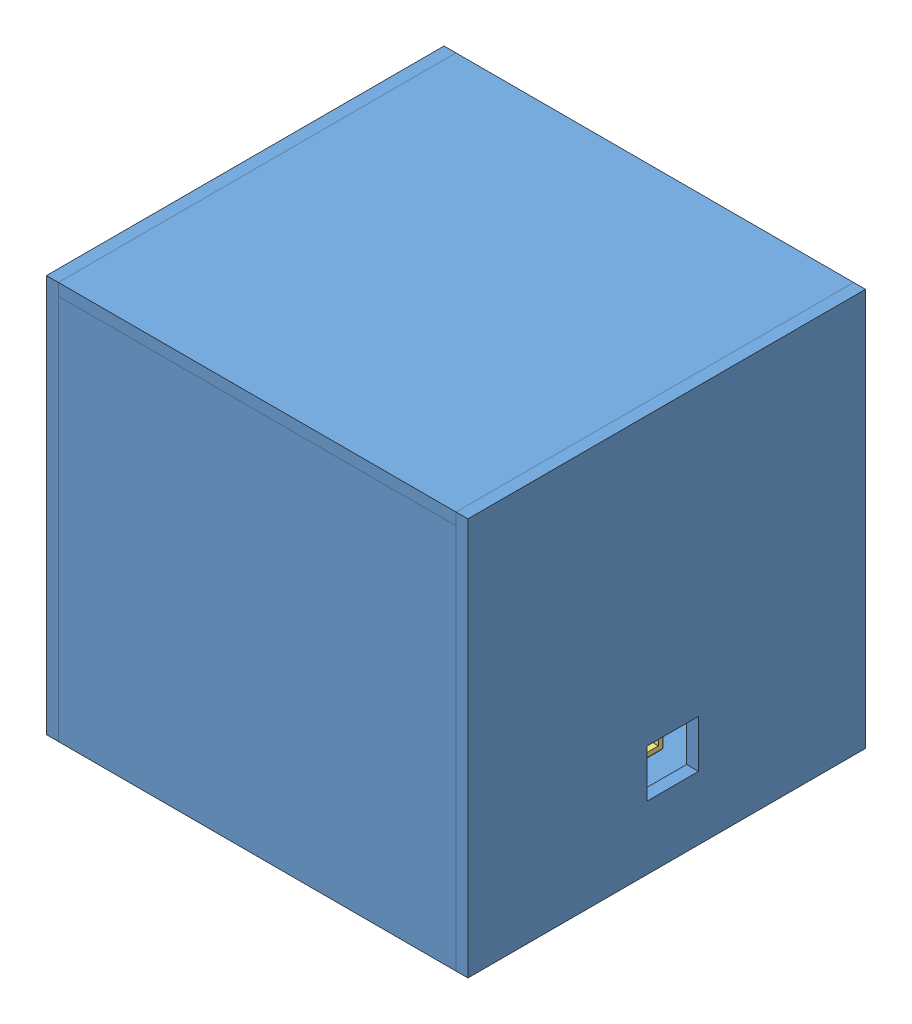
SolidWorks assembly config cube, configuration Default. Lengths in mm.
Overall size (106 103.17 100).
19 component instances, 4 part files, 36 mates.
Components (placement in the parent):
- Side-1: Side [holes] at (39.6067 40.9031 84.24) x (1 0 0) z (0 0 -1) size (100 3 94)
- 25x.5 Aluminum Hex Female Female Standoff-1: 25x.5 Aluminum Hex Female Female Standoff [Default] at (63.0067 47.2531 95.54) x (-0.497052 0 0.867721) z (0 1 0) size (6.35 8.06 12.7)
- 25x.5 Aluminum Hex Female Female Standoff-2: 25x.5 Aluminum Hex Female Female Standoff [Default] at (12.2067 47.2531 80.24) x (-0.915695 0 -0.401873) z (0 1 0) size (6.35 8.06 12.7)
- 25x.5 Aluminum Hex Female Female Standoff-3: 25x.5 Aluminum Hex Female Female Standoff [Default] at (12.2067 47.2531 52.34) x (0.973443 0 -0.22893) z (0 1 0) size (6.35 8.06 12.7)
- 25x.5 Aluminum Hex Female Female Standoff-4: 25x.5 Aluminum Hex Female Female Standoff [Default] at (64.6067 47.2531 47.24) x (-0.96108 0 -0.27627) z (0 1 0) size (6.35 8.06 12.7)
- ArduinoUno-1: ArduinoUno [Default] at (45.6067 53.6031 71.39) x (-1 0 0) z (0 0 -1) size (74.8 12.1 53.3)
- socket head cap screw_ai-2: socket head cap screw_ai [HX-SHCS 0.125-40x0.125x0.125-N] at (63.0067 58.3781 95.54) x (0 -1 0) z (0 0 1) size (6.35 5.21 5.21)
- socket head cap screw_ai-3: socket head cap screw_ai [HX-SHCS 0.125-40x0.125x0.125-N] at (12.2067 58.3781 80.24) x (0 -1 0) z (0 0 1) size (6.35 5.21 5.21)
- socket head cap screw_ai-4: socket head cap screw_ai [HX-SHCS 0.125-40x0.125x0.125-N] at (64.6067 58.3781 47.24) x (0 -1 0) z (0 0 1) size (6.35 5.21 5.21)
- socket head cap screw_ai-5: socket head cap screw_ai [HX-SHCS 0.125-40x0.125x0.125-N] at (12.2067 58.3781 52.34) x (0 -1 0) z (0 0 1) size (6.35 5.21 5.21)
- socket head cap screw_ai-6: socket head cap screw_ai [HX-SHCS 0.125-40x0.125x0.125-N] at (12.2067 34.7281 52.34) x (0 1 0) z (0 0 1) size (6.35 5.21 5.21)
- socket head cap screw_ai-7: socket head cap screw_ai [HX-SHCS 0.125-40x0.125x0.125-N] at (12.2067 34.7281 80.24) x (0 1 0) z (0 0 1) size (6.35 5.21 5.21)
- Side-3: Side [left right] at (-10.3933 87.9031 84.24) x (0 -1 0) z (0 0 -1) size (100 3 100)
- Side-4: Side [front back] at (39.6067 86.4031 131.24) x (1 0 0) z (0 -1 0) size (100 3 97)
- Side-5: Side [front back] at (39.6067 86.4031 34.24) x (1 0 0) z (0 -1 0) size (100 3 97)
- Side-6: Side [no holes] at (39.6067 137.9031 84.24) x (1 0 0) z (0 0 -1) size (100 3 100)
- Side-8: Side [left right hole] at (89.6067 87.9031 84.24) x (0 0 -1) z (0 -1 0) size (100 3 100)
- socket head cap screw_ai-13: socket head cap screw_ai [HX-SHCS 0.125-40x0.125x0.125-N] at (63.0067 34.7281 95.54) x (0 1 0) z (0 0 1) size (6.35 5.21 5.21)
- socket head cap screw_ai-14: socket head cap screw_ai [HX-SHCS 0.125-40x0.125x0.125-N] at (64.6067 34.7281 47.24) x (0 1 0) z (0 0 1) size (6.35 5.21 5.21)
Mates (geometry in assembly coordinates):
- Concentric5: concentric aligned: circle of 25x.5 Aluminum Hex Female Female Standoff-2; circle of ArduinoUno-1
- Coincident9: coincident anti-aligned: plane of 25x.5 Aluminum Hex Female Female Standoff-2 through (12.2067 53.6031 80.24) normal (0 1 0); plane of ArduinoUno-1 through (12.6067 53.6031 98.04) normal (0 -1 0)
- Concentric6: concentric anti-aligned: cylinder of ArduinoUno-1 through (63.0067 55.2031 95.54) axis (0 -1 0) radius 1.6; cylinder of socket head cap screw_ai-2 through (63.0067 90.1281 95.54) axis (0 1 0) radius 2.6035
- Coincident11: coincident anti-aligned: plane of ArduinoUno-1 through (12.6067 55.2031 98.04) normal (0 1 0); plane of socket head cap screw_ai-2 through (65.6102 55.2031 95.54) normal (0 -1 0)
- Concentric7: concentric anti-aligned: cylinder of ArduinoUno-1 through (12.2067 55.2031 80.24) axis (0 -1 0) radius 1.6; cylinder of socket head cap screw_ai-3 through (12.2067 90.1281 80.24) axis (0 1 0) radius 2.6035
- Coincident12: coincident anti-aligned: plane of ArduinoUno-1 through (12.6067 55.2031 98.04) normal (0 1 0); plane of socket head cap screw_ai-3 through (14.8102 55.2031 80.24) normal (0 -1 0)
- Concentric8: concentric anti-aligned: cylinder of ArduinoUno-1 through (64.6067 55.2031 47.24) axis (0 -1 0) radius 1.6; cylinder of socket head cap screw_ai-4 through (64.6067 90.1281 47.24) axis (0 1 0) radius 2.6035
- Coincident13: coincident anti-aligned: plane of ArduinoUno-1 through (12.6067 55.2031 98.04) normal (0 1 0); plane of socket head cap screw_ai-4 through (67.2102 55.2031 47.24) normal (0 -1 0)
- Concentric9: concentric anti-aligned: cylinder of ArduinoUno-1 through (12.2067 55.2031 52.34) axis (0 -1 0) radius 1.6; cylinder of socket head cap screw_ai-5 through (12.2067 90.1281 52.34) axis (0 1 0) radius 2.6035
- Coincident14: coincident anti-aligned: plane of ArduinoUno-1 through (12.6067 55.2031 98.04) normal (0 1 0); plane of socket head cap screw_ai-5 through (14.8102 55.2031 52.34) normal (0 -1 0)
- Concentric10: concentric aligned: cylinder of Side-1 through (12.2067 40.9031 52.34) axis (0 -1 0) radius 1.6; cylinder of socket head cap screw_ai-6 through (12.2067 2.9781 52.34) axis (0 -1 0) radius 2.6035
- Coincident15: coincident anti-aligned: plane of Side-1 through (39.6067 37.9031 84.24) normal (0 -1 0); plane of socket head cap screw_ai-6 through (9.6032 37.9031 52.34) normal (0 1 0)
- Concentric11: concentric aligned: cylinder of Side-1 through (12.2067 40.9031 80.24) axis (0 -1 0) radius 1.6; cylinder of socket head cap screw_ai-7 through (12.2067 2.9781 80.24) axis (0 -1 0) radius 2.6035
- Coincident16: coincident anti-aligned: plane of Side-1 through (39.6067 37.9031 84.24) normal (0 -1 0); plane of socket head cap screw_ai-7 through (9.6032 37.9031 80.24) normal (0 1 0)
- Coincident24: coincident anti-aligned: line of Side-1 through (89.6067 37.9031 131.24) axis (-1 0 0); line of Side-4 through (-10.3933 37.9031 131.24) axis (1 0 0)
- Concentric16: concentric aligned: circle of 25x.5 Aluminum Hex Female Female Standoff-1; circle of ArduinoUno-1
- Coincident29: coincident anti-aligned: circle of 25x.5 Aluminum Hex Female Female Standoff-1; plane of ArduinoUno-1 through (12.6067 53.6031 98.04) normal (0 -1 0)
- Concentric18: concentric aligned: cylinder of Side-1 through (63.0067 40.9031 95.54) axis (0 -1 0) radius 1.6; cylinder of socket head cap screw_ai-13 through (63.0067 2.9781 95.54) axis (0 -1 0) radius 2.6035
- Coincident31: coincident anti-aligned: plane of Side-1 through (39.6067 37.9031 84.24) normal (0 -1 0); plane of socket head cap screw_ai-13 through (60.4032 37.9031 95.54) normal (0 1 0)
- Concentric19: concentric aligned: cylinder of Side-1 through (64.6067 40.9031 47.24) axis (0 -1 0) radius 1.6; cylinder of socket head cap screw_ai-14 through (64.6067 2.9781 47.24) axis (0 -1 0) radius 2.6035
- Coincident32: coincident anti-aligned: plane of Side-1 through (39.6067 37.9031 84.24) normal (0 -1 0); plane of socket head cap screw_ai-14 through (62.0032 37.9031 47.24) normal (0 1 0)
- Concentric20: concentric anti-aligned: circle of Side-1; circle of 25x.5 Aluminum Hex Female Female Standoff-3
- Coincident33: coincident anti-aligned: plane of Side-1 through (39.6067 40.9031 84.24) normal (0 1 0); plane of 25x.5 Aluminum Hex Female Female Standoff-3 through (12.2067 40.9031 52.34) normal (0 -1 0)
- Concentric21: concentric aligned: circle of 25x.5 Aluminum Hex Female Female Standoff-4; circle of ArduinoUno-1
- Coincident36: coincident anti-aligned: circle of 25x.5 Aluminum Hex Female Female Standoff-4; plane of ArduinoUno-1 through (12.6067 53.6031 98.04) normal (0 -1 0)
- Concentric22: concentric aligned: circle of 25x.5 Aluminum Hex Female Female Standoff-3; circle of ArduinoUno-1
- Coincident38: coincident anti-aligned: circle of 25x.5 Aluminum Hex Female Female Standoff-3; plane of ArduinoUno-1 through (12.6067 53.6031 98.04) normal (0 -1 0)
- Concentric23: concentric aligned: circle of Side-1; circle of 25x.5 Aluminum Hex Female Female Standoff-1
- Coincident40: coincident aligned: line of Side-4 through (89.6067 134.9031 134.24) axis (-1 0 0); line of Side-6 through (89.6067 134.9031 134.24) axis (-1 0 0)
- Coincident41: coincident aligned: line of Side-4 through (-10.3933 134.9031 134.24) axis (0 0 -1); line of Side-6 through (-10.3933 134.9031 134.24) axis (0 0 -1)
- Coincident42: coincident aligned: line of Side-3 through (-10.3933 137.9031 34.24) axis (0 -1 0); line of Side-5 through (-10.3933 134.9031 34.24) axis (0 -1 0)
- Coincident43: coincident anti-aligned: line of Side-3 through (-10.3933 37.9031 134.24) axis (0 1 0); line of Side-4 through (-10.3933 134.9031 134.24) axis (0 -1 0)
- Coincident44: coincident anti-aligned: line of Side-1 through (-10.3933 37.9031 131.24) axis (0 0 -1); line of Side-3 through (-10.3933 37.9031 34.24) axis (0 0 1)
- Coincident45: coincident aligned: line of Side-1 through (-10.3933 37.9031 37.24) axis (1 0 0); line of Side-5 through (-10.3933 37.9031 37.24) axis (1 0 0)
- Coincident49: coincident anti-aligned: line of Side-4 through (89.6067 37.9031 134.24) axis (0 1 0); line of Side-8 through (89.6067 137.9031 134.24) axis (0 -1 0)
- Coincident50: coincident aligned: line of Side-6 through (89.6067 137.9031 34.24) axis (0 0 1); line of Side-8 through (89.6067 137.9031 34.24) axis (0 0 1)
